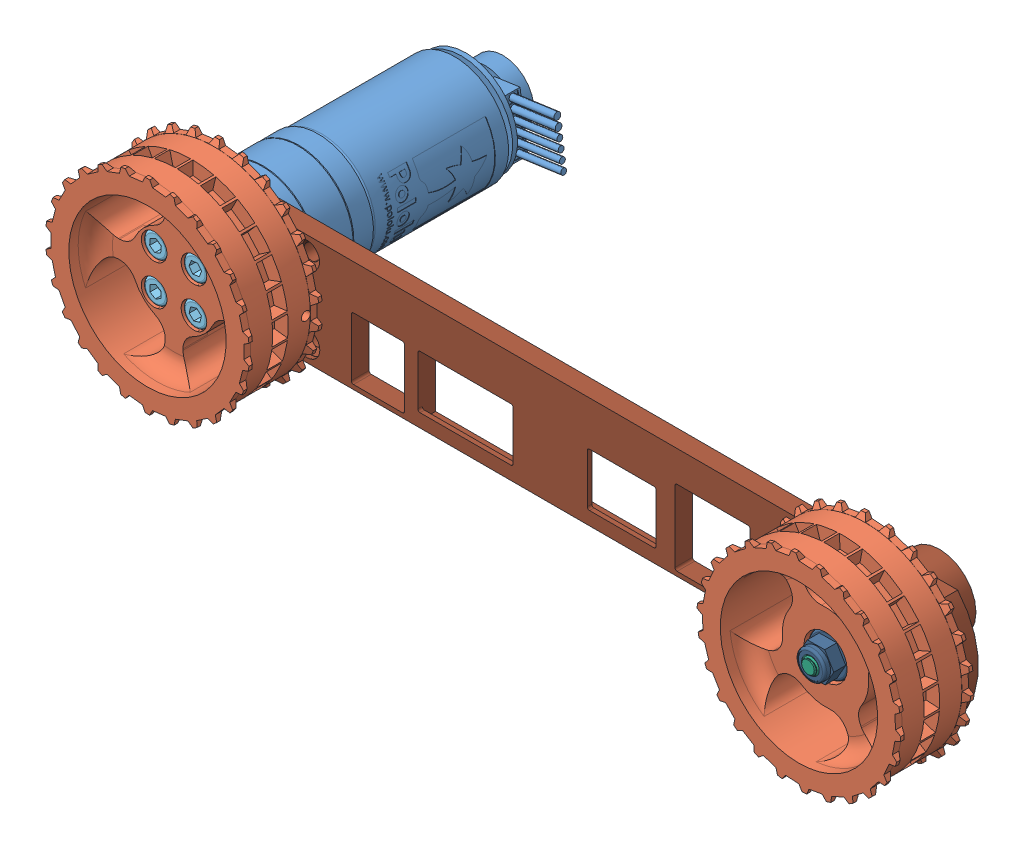
SolidWorks assembly wheels, configuration Right. Lengths in mm.
Overall size (207.65 62.92 81).
18 component instances, 11 part files, 11 mates.
Components (placement in the parent):
- wheel-powered-1: wheel-powered [Default] at (0.6984 4.2216 -21.5) x (0.139173 -0.990268 0) z (0 0 1) size (51.92 51.74 81)
  - wheel-motor-1: wheel-motor [Default] at (-36.8745 16.797 -18.375) x (0.990268 -0.139173 0) z (0 0 1) size (25 32.85 72)
  - wheel-body-1: wheel-body [Powered Visual] at (-6.3 12.5 5) x (0.990268 -0.139173 0) z (0 0 1) size (46 45.78 16.5)
  - wheel-motor-mount-1: wheel-motor-mount [Default] at (-6.3 12.5 5) x (0.990268 -0.139173 0) z (-0.139173 -0.990268 0) size (19 5 19)
  - M2.5-6mm-scrub-1: M2.5-6mm-scrub [Default] at (-6.0912 13.9854 7.5) x (0.990268 -0.139173 0) z (0 0 1) size (3.05 6.18 3.38)
  - M3-8mm-bolt-1: M3-8mm-bolt [Default] at (-10.1215 17.5713 15.2) x (1 0 0) z (0 1 0) size (5.5 10.77 5.5)
  - M3-8mm-bolt-2: M3-8mm-bolt [Default] at (-1.2287 16.3215 15.2) x (0.987351 0.158553 0) z (-0.158553 0.987351 0) size (5.5 10.77 5.5)
  - M3-8mm-bolt-4: M3-8mm-bolt [Default] at (-11.3713 8.6785 15.2) x (0.959125 0.282984 0) z (-0.282984 0.959125 0) size (5.5 10.77 5.5)
  - M3-8mm-bolt-6: M3-8mm-bolt [Default] at (-2.4785 7.4287 15.2) x (0.928571 0.371154 0) z (-0.371154 0.928571 0) size (5.5 10.77 5.5)
- wheel-free-1: wheel-free [Default] at (159.2 12.2 -33.24) x (-0.859884 -0.510489 0) z (0 0 1) size (45.78 46 33.24)
  - wheel-free-shaft-1: wheel-free-shaft [Default] x (1 0 0) z (0 -1 0) size (6 31.32 6)
  - wheel-free-bearing-1: wheel-free-bearing [Default] at (0 0 5.07) x (1 0 0) z (0 1 0) size (10 3.97 10)
  - wheel-free-bearing-2: wheel-free-bearing [Default] at (0 0 15.74) x (0.774434 0.632655 0) z (-0.632655 0.774434 0) size (10 3.97 10)
  - wheel-free-spacer-1: wheel-free-spacer [Default] at (0 0 16.74) x (0.90405 -0.427427 0) z (0.427427 0.90405 0) size (7 1 7)
  - wheel-free-pin-1: wheel-free-pin [Default] at (0 -4.75 18.2) x (0.907276 0 -0.420536) z (0.420536 0 0.907276) size (2 9.5 2)
  - wheel-body-1: wheel-body [Free] at (0 0 16.74) x (0 -1 0) z (0 0 1) size (46 45.78 16.5)
  - M4-nut-1: M4-nut [Default] at (0 0 25.24) x (1 0 0) z (0 -1 0) size (9.3 5.45 9.3)
- side-plate-1: side-plate [Right] at (12.2 43.075 -21.5) x (0 -1 0) z (0 0 1) size (25 185 14.2)
Mates (geometry in assembly coordinates):
- Coincident1: coincident aligned: plane of wheel-powered-1/wheel-body-1 through (12.2 12.2 0) normal (0 0 1); plane of wheel-free-1/wheel-body-1 through (159.2 12.2 0) normal (0 0 1)
- Coincident2: coincident aligned: plane of wheel-powered-1/wheel-body-1 through (12.2 12.2 0) normal (0 0 1); plane of assembly through (0 0 0) normal (0 0 1)
- Tangent1: tangent aligned: cylinder of wheel-free-1/wheel-body-1 through (159.2 12.2 0) axis (0 0 -1) radius 21.75; plane of assembly through (0 33.95 0) normal (0 1 0)
- Distance1: distance = 147 mm: line of wheel-powered-1/wheel-body-1 through (12.2 12.2 4.5) axis (0 0 -1); line of wheel-free-1/wheel-body-1 through (159.2 12.2 4.5) axis (0 0 -1)
- Parallel3: parallel aligned: plane of wheel-powered-1/wheel-motor-1 through (13.7 12.2 -17) normal (1 0 0); plane of assembly through (0 0 0) normal (1 0 0)
- Tangent2: tangent anti-aligned: cylinder of wheel-powered-1/wheel-motor-1 through (12.2 12.2 -69.3) axis (0 0 1) radius 12.2; plane of assembly through (0 0 0) normal (0 1 0)
- Tangent3: tangent anti-aligned: cylinder of wheel-powered-1/wheel-motor-1 through (12.2 12.2 -69.3) axis (0 0 1) radius 12.2; plane of assembly through (0 0 0) normal (1 0 0)
- InPlace3: in place: plane of ? through (12.2 12.2 -27.5) normal (0 0 1); plane of ? through (0 0 -27.5) normal (0 0 1); moOrthogonalPlaneRef_w of ? through (12.2 12.2 -27.5) normal (0 0 1); plane of ? through (0 0 -27.5) normal (0 1 0); plane of ? through (12.2 12.2 -27.5) normal (0 0 1); plane of ? through (0 0 -27.5) normal (1 0 0); plane of wheel-powered-1/wheel-motor-1 through (12.2 12.2 -21.5) normal (0 0 1); unknown of side-plate-1
- Coincident9: coincident aligned: plane of assembly through (12.2 12.2 -21.5) normal (0 0 1)
- Coincident10: coincident aligned: moOrthogonalPlaneRef_w of wheel-powered-1/wheel-motor-1 through (12.2 43.075 -21.5) normal (1 0 0); plane of side-plate-1
- Coincident11: coincident anti-aligned: moOrthogonalPlaneRef_w of wheel-powered-1/wheel-motor-1 through (12.2 43.075 -21.5) normal (0 1 0); plane of side-plate-1
